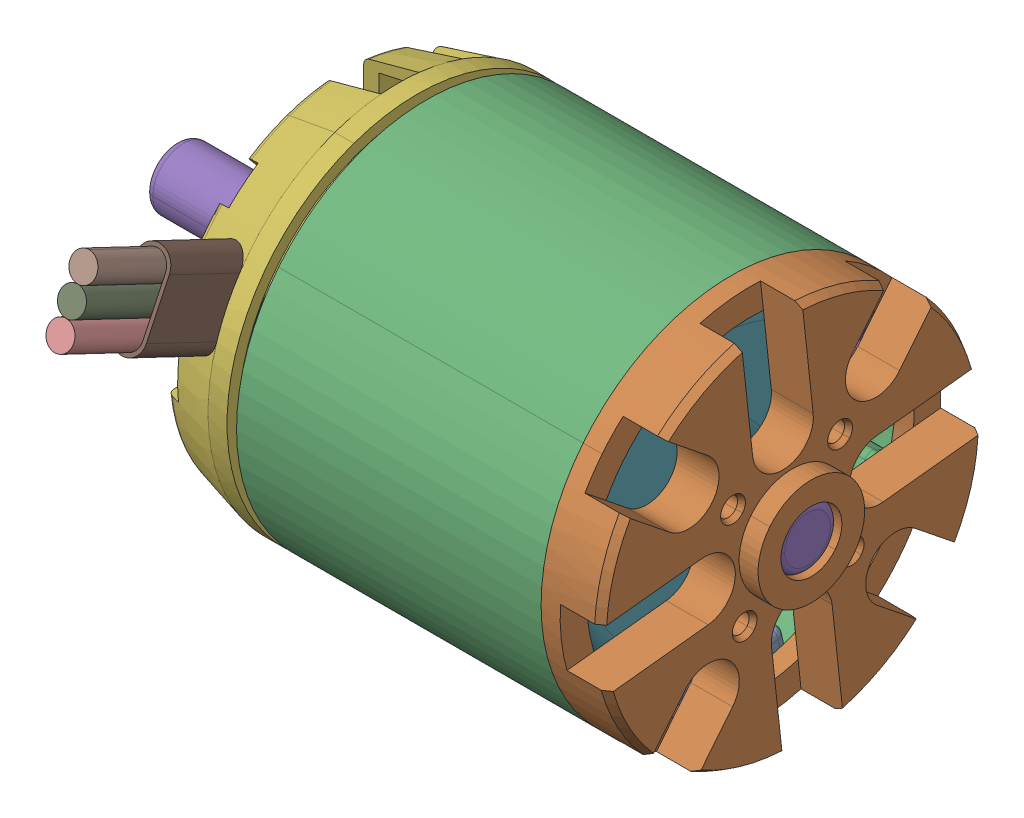
SolidWorks assembly RR_20238_50New N5056 BLDC MOTOR_V2_27_29_10 pm_31_12pm_9pm, configuration Default. Lengths in mm.
Overall size (83.5 70.3 78.03).
2 component instances, 2 part files, 2 mates.
Components (placement in the parent):
- RR_20238_50motor2_V2_27_29_10 pm_31_12pm_9pm-2: RR_20238_50motor2_V2_27_29_10 pm_31_12pm_9pm [Default] at (86.5004 37.0716 52.3291) size (83 50 67.88)
- RR_20238_50motor1_V2_27_29_10 pm_31_12pm_9pm-3: RR_20238_50motor1_V2_27_29_10 pm_31_12pm_9pm [Default] at (87.5004 37.0716 52.3291) x (1 0 0) z (0 0.626766 0.779207) size (50.5 50 50)
Mates (geometry in assembly coordinates):
- Concentric1: concentric: cylinder of motor2-2 through (85.5004 37.0716 52.3291) axis (-1 0 0) radius 20; cylinder of motor1-3 through (46.0004 37.0716 52.3291) axis (1 0 0) radius 25
- Distance1: distance = 59 mm anti-aligned: plane of motor2_V2-2 through (36.5004 37.0716 52.3291) normal (-1 0 0); plane of motor1_V2-3 through (95.5004 37.0716 52.3291) normal (1 0 0)
